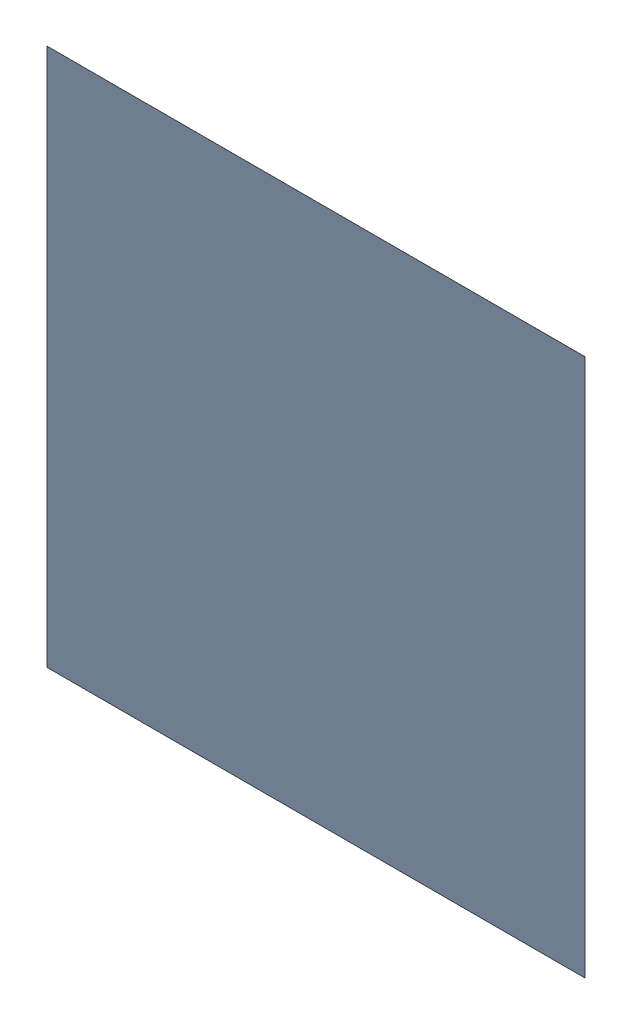
SolidWorks assembly X5, configuration Standard. Lengths in mm.
Overall size (0.05 0.05 0).
2 component instances, 1 part files, 0 mates.
Components (placement in the parent):
- 6269211456-1: 6269211456 [Standard] at (-6 -23.5 0) x (0 1 0) z (0 0 1) size (0.05 0.05 0)
  - Extruded-3-1: Extruded-3 [Standard] at origin size (0.05 0.05 0)
